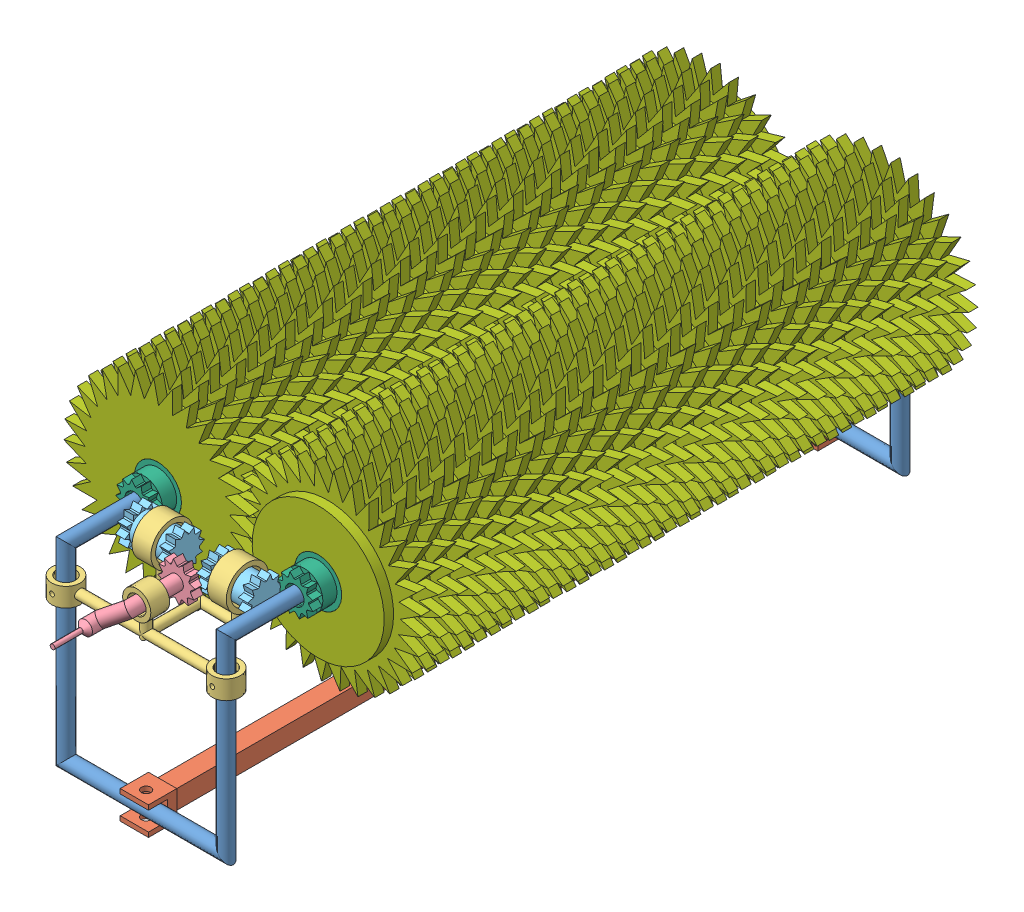
SolidWorks assembly Montaj1, configuration Varsayılan. Lengths in mm.
Overall size (57.69 41.88 79.55).
83 component instances, 7 part files, 27 mates.
Components (placement in the parent):
- sabitleyici-1: sabitleyici [Varsayılan] at (-0.178 -10.6973 31.125) size (18.5 21.5 20.75)
- altsabit-1: altsabit [Varsayılan] at (0.822 -10.6973 -4.625) x (0 0 1) z (-1 0 0) size (74 3 3)
- sabitleyici-2: sabitleyici [Varsayılan] at (-0.178 -10.6973 -40.375) x (-1 0 0) z (0 0 -1) size (18.5 21.5 20.75)
- kolsabıt-1: kolsabıt [Varsayılan] at (-0.178 5.3027 25.375) x (-1 0 0) z (0 0 -1) size (20 7 9.5)
- kol-1: kol [Varsayılan] at (-0.178 8.3027 27.925) x (0.627017 -0.779006 0) z (0 0 -1) size (4 6.88 11)
- cubuk2-1: cubuk2 [Varsayılan] at (1.322 9.0527 25.375) x (0 0.963499 0.267712) z (1 0 0) size (4 4 5.46)
- cubuk2-2: cubuk2 [Varsayılan] at (-7.192 9.0527 25.375) x (0 -0.835442 -0.549579) z (1 0 0) size (4 4 5.46)
- cubuk-1: cubuk [Varsayılan] at (8.322 9.3027 21.3734) x (0.713006 0.701158 0) z (0 0 -1) size (5 5 62.5)
- uzun_silindir-1: uzun_silindir [Varsayılan] at (8.9726 13.9935 25.139) x (0.806091 0.591792 0) z (0 0 -1) size (29.16 29.16 60)
  - kısa_sılındır-1: kısa_sılındır [Varsayılan] at (-17.2962 -1.6546 23.1558) size (23.52 23.52 10)
    - Parça1-3: Parça1 [Varsayılan] at (13.9957 5.0507 15.6098) size (20 20 2)
    - Parça1-4: Parça1 [Varsayılan] at (13.9957 5.0507 11.6098) x (0.980785 0.19509 0) z (0 0 1) size (20 20 2)
    - Parça1-5: Parça1 [Varsayılan] at (13.9957 5.0507 13.6098) x (0.994056 0.108867 0) z (0 0 1) size (20 20 2)
    - Parça1-6: Parça1 [Varsayılan] at (13.9957 5.0507 17.6098) x (0.996195 -0.087156 0) z (0 0 1) size (20 20 2)
    - Parça1-7: Parça1 [Varsayılan] at (13.9957 5.0507 19.6098) x (0.980785 -0.19509 0) z (0 0 1) size (20 20 2)
  - kısa_sılındır-2: kısa_sılındır [Varsayılan] at (-16.6632 -3.1482 33.1558) x (0.994056 0.108867 0) z (0 0 1) size (23.52 23.52 10)
    - Parça1-3: Parça1 [Varsayılan] at (13.9957 5.0507 15.6098) size (20 20 2)
    - Parça1-4: Parça1 [Varsayılan] at (13.9957 5.0507 11.6098) x (0.980785 0.19509 0) z (0 0 1) size (20 20 2)
    - Parça1-5: Parça1 [Varsayılan] at (13.9957 5.0507 13.6098) x (0.994056 0.108867 0) z (0 0 1) size (20 20 2)
    - Parça1-6: Parça1 [Varsayılan] at (13.9957 5.0507 17.6098) x (0.996195 -0.087156 0) z (0 0 1) size (20 20 2)
    - Parça1-7: Parça1 [Varsayılan] at (13.9957 5.0507 19.6098) x (0.980785 -0.19509 0) z (0 0 1) size (20 20 2)
  - kısa_sılındır-3: kısa_sılındır [Varsayılan] at (-15.8713 -4.5641 43.1558) x (0.976296 0.21644 0) z (0 0 1) size (23.52 23.52 10)
    - Parça1-3: Parça1 [Varsayılan] at (13.9957 5.0507 15.6098) size (20 20 2)
    - Parça1-4: Parça1 [Varsayılan] at (13.9957 5.0507 11.6098) x (0.980785 0.19509 0) z (0 0 1) size (20 20 2)
    - Parça1-5: Parça1 [Varsayılan] at (13.9957 5.0507 13.6098) x (0.994056 0.108867 0) z (0 0 1) size (20 20 2)
    - Parça1-6: Parça1 [Varsayılan] at (13.9957 5.0507 17.6098) x (0.996195 -0.087156 0) z (0 0 1) size (20 20 2)
    - Parça1-7: Parça1 [Varsayılan] at (13.9957 5.0507 19.6098) x (0.980785 -0.19509 0) z (0 0 1) size (20 20 2)
  - kısa_sılındır-4: kısa_sılındır [Varsayılan] at (-15.3237 -5.3692 13.1558) x (0.96005 0.279829 0) z (0 0 1) size (23.52 23.52 10)
    - Parça1-3: Parça1 [Varsayılan] at (13.9957 5.0507 15.6098) size (20 20 2)
    - Parça1-4: Parça1 [Varsayılan] at (13.9957 5.0507 11.6098) x (0.980785 0.19509 0) z (0 0 1) size (20 20 2)
    - Parça1-5: Parça1 [Varsayılan] at (13.9957 5.0507 13.6098) x (0.994056 0.108867 0) z (0 0 1) size (20 20 2)
    - Parça1-6: Parça1 [Varsayılan] at (13.9957 5.0507 17.6098) x (0.996195 -0.087156 0) z (0 0 1) size (20 20 2)
    - Parça1-7: Parça1 [Varsayılan] at (13.9957 5.0507 19.6098) x (0.980785 -0.19509 0) z (0 0 1) size (20 20 2)
  - kısa_sılındır-5: kısa_sılındır [Varsayılan] at (-18.0126 1.1729 3.1558) x (0.980785 -0.19509 0) z (0 0 1) size (23.52 23.52 10)
    - Parça1-3: Parça1 [Varsayılan] at (13.9957 5.0507 15.6098) size (20 20 2)
    - Parça1-4: Parça1 [Varsayılan] at (13.9957 5.0507 11.6098) x (0.980785 0.19509 0) z (0 0 1) size (20 20 2)
    - Parça1-5: Parça1 [Varsayılan] at (13.9957 5.0507 13.6098) x (0.994056 0.108867 0) z (0 0 1) size (20 20 2)
    - Parça1-6: Parça1 [Varsayılan] at (13.9957 5.0507 17.6098) x (0.996195 -0.087156 0) z (0 0 1) size (20 20 2)
    - Parça1-7: Parça1 [Varsayılan] at (13.9957 5.0507 19.6098) x (0.980785 -0.19509 0) z (0 0 1) size (20 20 2)
  - kısa_sılındır-6: kısa_sılındır [Varsayılan] at (-17.6831 -0.4155 -6.8442) x (0.996195 -0.087156 0) z (0 0 1) size (23.52 23.52 10)
    - Parça1-3: Parça1 [Varsayılan] at (13.9957 5.0507 15.6098) size (20 20 2)
    - Parça1-4: Parça1 [Varsayılan] at (13.9957 5.0507 11.6098) x (0.980785 0.19509 0) z (0 0 1) size (20 20 2)
    - Parça1-5: Parça1 [Varsayılan] at (13.9957 5.0507 13.6098) x (0.994056 0.108867 0) z (0 0 1) size (20 20 2)
    - Parça1-6: Parça1 [Varsayılan] at (13.9957 5.0507 17.6098) x (0.996195 -0.087156 0) z (0 0 1) size (20 20 2)
    - Parça1-7: Parça1 [Varsayılan] at (13.9957 5.0507 19.6098) x (0.980785 -0.19509 0) z (0 0 1) size (20 20 2)
- cubuk-2: cubuk [Varsayılan] at (-8.678 9.3027 21.3734) x (0.931416 -0.363956 0) z (0 0 -1) size (5 5 62.5)
- uzun_silindir-2: uzun_silindir [Varsayılan] at (-7.7909 13.9546 -42.3923) x (-0.573893 0.81893 0) z (0 0 1) size (29.16 29.16 60)
  - kısa_sılındır-1: kısa_sılındır [Varsayılan] at (-17.2962 -1.6546 23.1558) size (23.52 23.52 10)
    - Parça1-3: Parça1 [Varsayılan] at (13.9957 5.0507 15.6098) size (20 20 2)
    - Parça1-4: Parça1 [Varsayılan] at (13.9957 5.0507 11.6098) x (0.980785 0.19509 0) z (0 0 1) size (20 20 2)
    - Parça1-5: Parça1 [Varsayılan] at (13.9957 5.0507 13.6098) x (0.994056 0.108867 0) z (0 0 1) size (20 20 2)
    - Parça1-6: Parça1 [Varsayılan] at (13.9957 5.0507 17.6098) x (0.996195 -0.087156 0) z (0 0 1) size (20 20 2)
    - Parça1-7: Parça1 [Varsayılan] at (13.9957 5.0507 19.6098) x (0.980785 -0.19509 0) z (0 0 1) size (20 20 2)
  - kısa_sılındır-2: kısa_sılındır [Varsayılan] at (-16.6632 -3.1482 33.1558) x (0.994056 0.108867 0) z (0 0 1) size (23.52 23.52 10)
    - Parça1-3: Parça1 [Varsayılan] at (13.9957 5.0507 15.6098) size (20 20 2)
    - Parça1-4: Parça1 [Varsayılan] at (13.9957 5.0507 11.6098) x (0.980785 0.19509 0) z (0 0 1) size (20 20 2)
    - Parça1-5: Parça1 [Varsayılan] at (13.9957 5.0507 13.6098) x (0.994056 0.108867 0) z (0 0 1) size (20 20 2)
    - Parça1-6: Parça1 [Varsayılan] at (13.9957 5.0507 17.6098) x (0.996195 -0.087156 0) z (0 0 1) size (20 20 2)
    - Parça1-7: Parça1 [Varsayılan] at (13.9957 5.0507 19.6098) x (0.980785 -0.19509 0) z (0 0 1) size (20 20 2)
  - kısa_sılındır-3: kısa_sılındır [Varsayılan] at (-15.8713 -4.5641 43.1558) x (0.976296 0.21644 0) z (0 0 1) size (23.52 23.52 10)
    - Parça1-3: Parça1 [Varsayılan] at (13.9957 5.0507 15.6098) size (20 20 2)
    - Parça1-4: Parça1 [Varsayılan] at (13.9957 5.0507 11.6098) x (0.980785 0.19509 0) z (0 0 1) size (20 20 2)
    - Parça1-5: Parça1 [Varsayılan] at (13.9957 5.0507 13.6098) x (0.994056 0.108867 0) z (0 0 1) size (20 20 2)
    - Parça1-6: Parça1 [Varsayılan] at (13.9957 5.0507 17.6098) x (0.996195 -0.087156 0) z (0 0 1) size (20 20 2)
    - Parça1-7: Parça1 [Varsayılan] at (13.9957 5.0507 19.6098) x (0.980785 -0.19509 0) z (0 0 1) size (20 20 2)
  - kısa_sılındır-4: kısa_sılındır [Varsayılan] at (-15.3237 -5.3692 13.1558) x (0.96005 0.279829 0) z (0 0 1) size (23.52 23.52 10)
    - Parça1-3: Parça1 [Varsayılan] at (13.9957 5.0507 15.6098) size (20 20 2)
    - Parça1-4: Parça1 [Varsayılan] at (13.9957 5.0507 11.6098) x (0.980785 0.19509 0) z (0 0 1) size (20 20 2)
    - Parça1-5: Parça1 [Varsayılan] at (13.9957 5.0507 13.6098) x (0.994056 0.108867 0) z (0 0 1) size (20 20 2)
    - Parça1-6: Parça1 [Varsayılan] at (13.9957 5.0507 17.6098) x (0.996195 -0.087156 0) z (0 0 1) size (20 20 2)
    - Parça1-7: Parça1 [Varsayılan] at (13.9957 5.0507 19.6098) x (0.980785 -0.19509 0) z (0 0 1) size (20 20 2)
  - kısa_sılındır-5: kısa_sılındır [Varsayılan] at (-18.0126 1.1729 3.1558) x (0.980785 -0.19509 0) z (0 0 1) size (23.52 23.52 10)
    - Parça1-3: Parça1 [Varsayılan] at (13.9957 5.0507 15.6098) size (20 20 2)
    - Parça1-4: Parça1 [Varsayılan] at (13.9957 5.0507 11.6098) x (0.980785 0.19509 0) z (0 0 1) size (20 20 2)
    - Parça1-5: Parça1 [Varsayılan] at (13.9957 5.0507 13.6098) x (0.994056 0.108867 0) z (0 0 1) size (20 20 2)
    - Parça1-6: Parça1 [Varsayılan] at (13.9957 5.0507 17.6098) x (0.996195 -0.087156 0) z (0 0 1) size (20 20 2)
    - Parça1-7: Parça1 [Varsayılan] at (13.9957 5.0507 19.6098) x (0.980785 -0.19509 0) z (0 0 1) size (20 20 2)
  - kısa_sılındır-6: kısa_sılındır [Varsayılan] at (-17.6831 -0.4155 -6.8442) x (0.996195 -0.087156 0) z (0 0 1) size (23.52 23.52 10)
    - Parça1-3: Parça1 [Varsayılan] at (13.9957 5.0507 15.6098) size (20 20 2)
    - Parça1-4: Parça1 [Varsayılan] at (13.9957 5.0507 11.6098) x (0.980785 0.19509 0) z (0 0 1) size (20 20 2)
    - Parça1-5: Parça1 [Varsayılan] at (13.9957 5.0507 13.6098) x (0.994056 0.108867 0) z (0 0 1) size (20 20 2)
    - Parça1-6: Parça1 [Varsayılan] at (13.9957 5.0507 17.6098) x (0.996195 -0.087156 0) z (0 0 1) size (20 20 2)
    - Parça1-7: Parça1 [Varsayılan] at (13.9957 5.0507 19.6098) x (0.980785 -0.19509 0) z (0 0 1) size (20 20 2)
Mates (geometry in assembly coordinates):
- Eş Merkezli1: concentric: sabitleyici-1, altsabit-1
- Genişlik1: width: altsabit-1, sabitleyici-1
- Eş Merkezli2: concentric: altsabit-1, sabitleyici-2
- Genişlik2: width: altsabit-1, sabitleyici-2
- Eş Merkezli3: concentric: sabitleyici-1, sabitleyici-2
- Eş Merkezli4: concentric: sabitleyici-1, kolsabıt-1
- Eş Merkezli5: concentric: sabitleyici-1, kolsabıt-1
- Eş Merkezli6: concentric: sabitleyici-1, kolsabıt-1
- Eş Merkezli8: concentric: kolsabıt-1, kol-1
- Eş Merkezli9: concentric: kolsabıt-1, cubuk2-1
- Eş Merkezli10: concentric: kolsabıt-1, cubuk2-2
- GearMate1: gear: kol-1, cubuk2-1
- Teğet1: tangent: kol-1, cubuk2-1
- Uzaklık1: distance: kol-1, kolsabıt-1
- Eş Merkezli11: concentric: sabitleyici-1, cubuk-1
- GearMate2: gear: cubuk-1, cubuk2-1
- Teğet2: tangent: cubuk2-1, cubuk-1
- GearMate3: gear: cubuk2-2, kol-1
- Eş Merkezli13: concentric: sabitleyici-1, cubuk-2
- GearMate4: gear: cubuk2-2, cubuk-2
- Teğet4: tangent: cubuk2-2, cubuk-2
- Eş Merkezli19: concentric: cubuk-1, uzun_silindir-1
- Eş Merkezli20: concentric: cubuk-2, uzun_silindir-2
- Çakışık7: coincident: cubuk-2, uzun_silindir-2
- Çakışık8: coincident: cubuk-1, uzun_silindir-1
- Kilitle4: lock: cubuk-1, uzun_silindir-1
- Kilitle5: lock: cubuk-2, uzun_silindir-2
